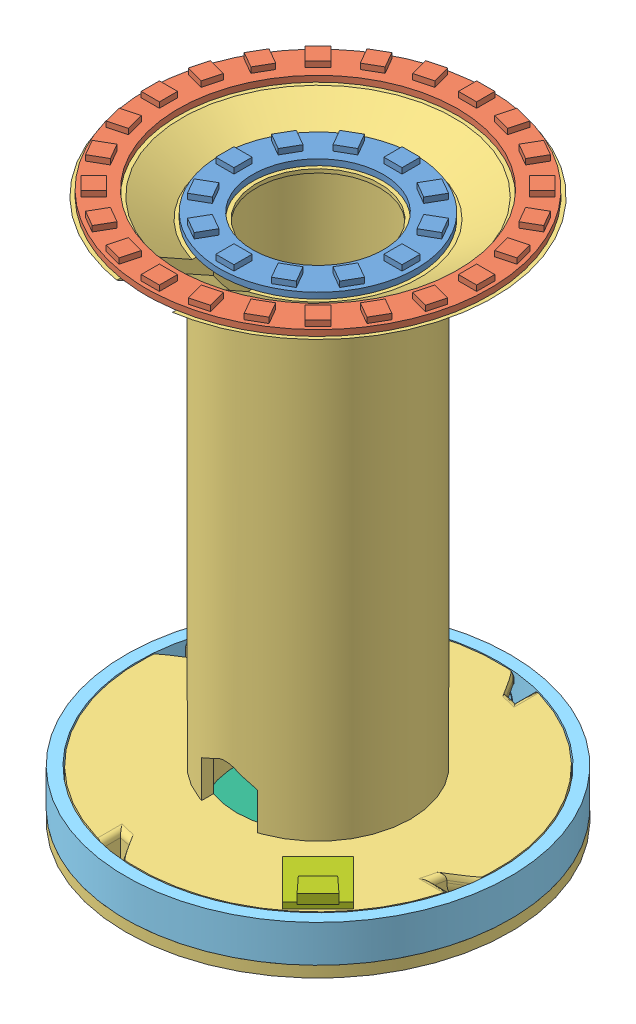
SolidWorks assembly 灯芯, configuration 默认. Lengths in mm.
Overall size (103.6 148.97 103.6).
7 component instances, 7 part files, 23 mates.
Components (placement in the parent):
- 灯环ws2812_12-1: 灯环ws2812_12 [默认] at origin size (52.9 3.1 52.9)
- 灯环ws2812_24-1: 灯环ws2812_24 [默认] at (0 5.3116 0) size (92.6 3.1 92.6)
- 灯柱-2: 灯柱 [默认] at origin size (103.6 145.87 103.6)
- c8t6开发板-1: c8t6开发板 [默认] at (0 -93.6633 0) x (1 0 0) z (0 -1 0) size (34.2 11.2 67.8)
- 灯罩-1: 灯罩 [默认] at (0 -137.5633 0) size (103.6 10 103.6)
- 底座盖-1: 底座盖 [默认] at (0 -140.5633 0) size (47.4 1.8 47.4)
- microUSB板-1: microUSB板 [默认] at (28.1428 -127.5633 28.1428) x (-0.707107 0 -0.707107) z (0.707107 0 -0.707107) size (15.8 4.1 13.57)
Mates (geometry in assembly coordinates):
- 重合8: coincident aligned: plane of 灯环ws2812_12-1 through (0 0 0) normal (0 0 1); plane of assembly through (0 0 0) normal (0 0 1)
- 重合9: coincident aligned: plane of 灯环ws2812_12-1 through (0 0 0) normal (0 1 0); plane of assembly through (0 0 0) normal (0 1 0)
- 重合10: coincident aligned: plane of 灯环ws2812_12-1 through (0 0 0) normal (1 0 0); plane of assembly through (0 0 0) normal (1 0 0)
- 重合11: coincident aligned: plane of 灯环ws2812_12-1 through (0 0 0) normal (1 0 0); plane of 灯柱-2 through (0 0 0) normal (1 0 0)
- 重合12: coincident aligned: plane of 灯环ws2812_12-1 through (0 0 0) normal (0 1 0); plane of 灯柱-2 through (0 0 0) normal (0 1 0)
- 重合13: coincident aligned: plane of 灯环ws2812_12-1 through (0 0 0) normal (0 0 1); plane of 灯柱-2 through (0 0 0) normal (0 0 1)
- 重合14: coincident aligned: plane of 灯环ws2812_12-1 through (0 0 0) normal (0 0 1); plane of 灯环ws2812_24-1 through (0 5.3116 0) normal (0 0 1)
- 重合15: coincident aligned: plane of 灯环ws2812_12-1 through (0 0 0) normal (1 0 0); plane of 灯环ws2812_24-1 through (0 5.3116 0) normal (1 0 0)
- 重合16: coincident anti-aligned: plane of 灯环ws2812_24-1 through (0 5.3116 0) normal (0 -1 0); plane of 灯柱-2 through (0 5.3116 -36.65) normal (0 1 0)
- 重合17: coincident aligned: plane of 灯柱-2 through (0 0 0) normal (1 0 0); plane of c8t6开发板-1 through (0 -93.6633 0) normal (1 0 0)
- 平行1: parallel aligned: plane of 灯柱-2 through (0 0 0) normal (0 0 1); plane of c8t6开发板-1 through (0 -93.6633 0) normal (0 0 1)
- 重合18: coincident aligned: plane of 灯柱-2 through (0 0 0) normal (0 0 1); plane of c8t6开发板-1 through (0 -93.6633 0) normal (0 0 1)
- 重合19: coincident anti-aligned: plane of 灯柱-2 through (0 -127.5633 -25) normal (0 1 0); plane of c8t6开发板-1 through (-17.1 -127.5633 11.2) normal (0 -1 0)
- 重合20: coincident aligned: plane of 灯柱-2 through (0 0 0) normal (0 0 1); plane of 灯罩-1 through (0 -137.5633 0) normal (0 0 1)
- 重合21: coincident aligned: plane of 灯柱-2 through (0 0 0) normal (1 0 0); plane of 灯罩-1 through (0 -137.5633 0) normal (1 0 0)
- 重合22: coincident aligned: plane of 灯柱-2 through (0 -137.5633 -48.3) normal (0 1 0); plane of 灯罩-1 through (0 -137.5633 0) normal (0 1 0)
- 重合23: coincident aligned: plane of 灯柱-2 through (0 0 0) normal (0 0 1); plane of 底座盖-1 through (0 -140.5633 0) normal (0 0 1)
- 重合24: coincident aligned: plane of 灯柱-2 through (0 0 0) normal (1 0 0); plane of 底座盖-1 through (0 -140.5633 0) normal (1 0 0)
- 重合25: coincident anti-aligned: plane of 灯柱-2 through (0 -140.5633 -51.8) normal (0 -1 0); plane of 底座盖-1 through (0 -140.5633 0) normal (0 1 0)
- 重合26: coincident anti-aligned: plane of 灯柱-2 through (0 -127.5633 -25) normal (0 1 0); plane of microUSB板-1 through (27.5772 -127.5633 27.5772) normal (0 -1 0)
- 重合27: coincident: axis of 灯柱-2 through (0 -137.5633 0) axis (0 1 0); plane of microUSB板-1 through (27.5772 -127.5633 27.5772) normal (0.707107 0 -0.707107)
- 距离3: distance = 0.2 mm aligned: plane of microUSB板-1 through (36.8403 -123.4633 31.1834) normal (0.707107 0 0.707107); cylinder of 灯柱-2 through (0 0 0) axis (0 1 0) radius 48.3
- 角度1: planar angle = 0.785398 rad aligned: plane of microUSB板-1 through (28.1428 -127.5633 28.1428) normal (0.707107 0 -0.707107); plane of assembly
